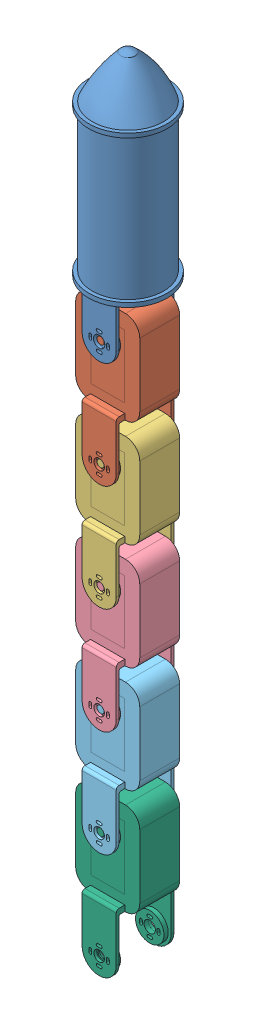
SolidWorks assembly test5, configuration 預設. Lengths in mm.
Overall size (55 553.48 55).
6 component instances, 6 part files, 22 mates.
Components (placement in the parent):
- base_link2-2: base_link2 [預設] at origin size (55 179.98 55)
- link1-1: link1 [預設] at (0 -157.7 0) x (0 1 0) z (0 0 -1) size (107 45 40.5)
- link2-1: link2 [預設] at (0 -232.4 0) x (0 1 0) z (0 0 -1) size (107 45 40.5)
- link3-2: link3 [預設] at (0 -307.1 0) x (0 1 0) z (0 0 -1) size (107 45 40.5)
- link4-1: link4 [預設] at (0 -381.8 0) x (0 1 0) z (0 0 -1) size (107 45 40.5)
- link5-1: link5 [預設] at (0 -456.5 0) x (0 1 0) z (0 0 -1) size (107 45 40.5)
Mates (geometry in assembly coordinates):
- 平行相距4: distance = 18.5 mm: plane of base_link2-2 through (0 -83 -18.5) normal (0 0 1); plane of assembly through (0 0 0) normal (0 0 1)
- 平行相距5: distance = 12 mm: plane of assembly through (0 0 0) normal (1 0 0); plane of base_link2-2 through (12 -53 18) normal (1 0 0)
- 平行相距6: distance = 50 mm: plane of assembly through (0 0 0) normal (0 1 0); plane of base_link2-2 through (0 -50 -0.25) normal (0 1 0)
- 同軸心2: concentric: cylinder of base_link2-2 through (0 -83 18) axis (0 0 1) radius 4; cylinder of link1-1 through (0 -83 14) axis (0 0 1) radius 2.5
- 同軸心3: concentric: cylinder of base_link2-2 through (0 -83 -20.5) axis (0 0 1) radius 4; cylinder of link1-1 through (0 -83 -19) axis (0 0 1) radius 2.5
- 平行1: parallel: plane of base_link2-2 through (12 -53 -20.5) normal (1 0 0); plane of link1-1 through (22.5 -127.7 -14) normal (1 0 0)
- 重合/共線/共點8: coincident: plane of base_link2-2 through (0 -83 -18.5) normal (0 0 1); plane of link1-1 through (0 -157.7 -18.5) normal (0 0 1)
- 同軸心4: concentric: cylinder of link1-1 through (0 -157.7 20) axis (0 0 -1) radius 3.7; cylinder of ? through (122.3295 -185.6512 7.75) axis (0 0 -1) radius 2.5
- 重合/共線/共點9: coincident: plane of link1-1 through (22.5 -127.7 -14) normal (1 0 0); plane of ?
- 重合/共線/共點10: coincident: plane of link1-1 through (0 -67.7653 20) normal (0 0 1); plane of ?
- 重合/共線/共點11: coincident: plane of link1-1 through (22.5 -127.7 -14) normal (1 0 0); plane of link2-1 through (22.5 -202.4 -14) normal (1 0 0)
- 同軸心5: concentric: cylinder of link1-1 through (0 -157.7 20) axis (0 0 -1) radius 3.7; cylinder of link2-1 through (0 -157.7 14) axis (0 0 1) radius 2.5
- 重合/共線/共點12: coincident: plane of link1-1 through (0 -67.7653 14) normal (0 0 1); plane of link2-1 through (0 -142.4653 14) normal (0 0 1)
- 重合/共線/共點14: coincident: plane of link2-1 through (22.5 -202.4 -14) normal (1 0 0); plane of link3-2 through (22.5 -277.1 -14) normal (1 0 0)
- 同軸心6: concentric: cylinder of link2-1 through (0 -232.4 -18.5) axis (0 0 -1) radius 4; cylinder of link3-2 through (0 -232.4 -19) axis (0 0 1) radius 2.5
- 重合/共線/共點15: coincident: plane of link2-1 through (0 -142.4653 -14) normal (0 0 -1); plane of link3-2 through (0 -217.1653 -14) normal (0 0 -1)
- 同軸心7: concentric: cylinder of link3-2 through (0 -307.1 20) axis (0 0 -1) radius 3.7; cylinder of link4-1 through (0 -307.1 14) axis (0 0 1) radius 2.5
- 重合/共線/共點16: coincident: plane of link3-2 through (22.5 -277.1 -14) normal (1 0 0); plane of link4-1 through (22.5 -351.8 -14) normal (1 0 0)
- 重合/共線/共點17: coincident: plane of link3-2 through (0 -217.1653 14) normal (0 0 1); plane of link4-1 through (0 -291.8653 14) normal (0 0 1)
- 重合/共線/共點18: coincident: plane of link4-1 through (22.5 -351.8 -14) normal (1 0 0); plane of link5-1 through (22.5 -426.5 -14) normal (1 0 0)
- 同軸心8: concentric: cylinder of link4-1 through (0 -381.8 20) axis (0 0 -1) radius 3.7; cylinder of link5-1 through (0 -381.8 14) axis (0 0 1) radius 2.5
- 重合/共線/共點19: coincident: plane of link4-1 through (0 -291.8653 14) normal (0 0 1); plane of link5-1 through (0 -366.5653 14) normal (0 0 1)
